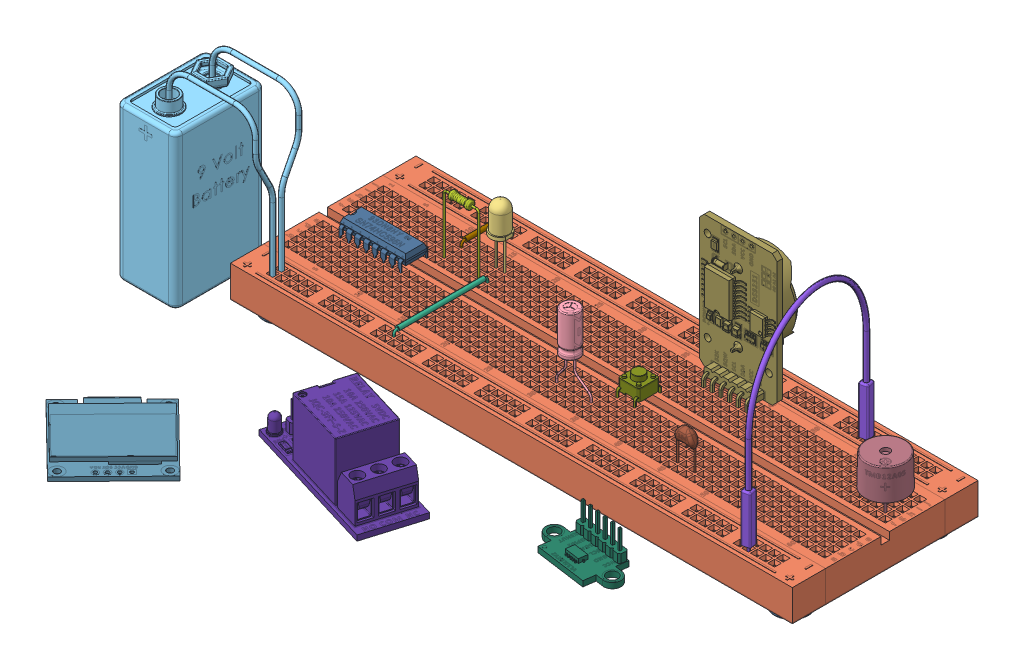
SolidWorks assembly BREADBOARD Test Unit, configuration Default. Lengths in mm.
Overall size (190.32 64.05 125.75).
17 component instances, 17 part files, 38 mates.
Components (placement in the parent):
- Breadboard Footpads-1: Breadboard Footpads [Default] at origin size (161.04 2.95 51.04)
- Breadboard-1: Breadboard [Default] at (0 3.15 0) x (0 0 -1) z (1 0 0) size (54.5 9.3 165)
- LED-Red-1: LED-Red [Default] at (-41.91 20.65 -11.43) x (0 0 -1) z (1 0 0) size (5.7 26.25 5.45)
- Bent Cap-1: Bent Cap [Default] at (-1.08 20.6268 8.89) x (0 0 1) z (-1 0 0) size (5.3 27.48 10.66)
- 9-Volt Battery-1: 9-Volt Battery [Default] at (-99.0282 0 22.375) x (0 0 1) z (-1 0 0) size (26.47 55.61 34.84)
- Jumper Wire BLACK GND-1: Jumper Wire BLACK GND [Default] at (-40.64 12.9 7.3775) x (0 0 -1) z (1 0 0) size (28.05 6.65 1.3)
- Resistor 470 Ohm-1: Resistor 470 Ohm [Default] at (-48.26 28.55 -6.35) size (10.69 26.62 2.44)
- Duport M-M Wire RED-01-1: Duport M-M Wire RED-01 [Default] at (60.96 13.25 1.2699) x (-0.221404 0 -0.975182) z (0.975182 0 -0.221404) size (48.43 57.2 2.54)
- Jumper Wire RED-1: Jumper Wire RED [Default] at (-53.34 12.9 -16.2675) x (0 0 -1) z (1 0 0) size (10.27 6.65 1.3)
- SN74HC595N Shift Register-1: SN74HC595N Shift Register [Default] at (-64.77 14.2 0) x (0 0 -1) z (1 0 0) size (7.9 7.3 19.3)
- Capacitor Ceramic 104 100nf-2: Capacitor Ceramic 104 100nf [Default] at (35.56 17.6608 11.43) size (5.72 13.92 2.54)
- DS3231 RTC-1: DS3231 RTC [Default] at (24.13 32.3828 -15.23) x (0 1 0) z (0 0 1) size (44.75 22.8 13.53)
- Buzzer Active 5V-1: Buzzer Active 5V [Default] at (73.5456 15.2644 -9.0832) x (0.717364 0 -0.696699) z (0.696699 0 0.717364) size (12 15 12)
- 0.96 Inch OLED Display Module I2C-1: 0.96 Inch OLED Display Module I2C [Default] at (-65.2768 2.2 78.9509) x (-0.714956 0 -0.69917) z (0.69917 0 -0.714956) size (27.8 4.2 27.5)
- Laser Ranging Sensor VL53L0XV2-1: Laser Ranging Sensor VL53L0XV2 [Default] at (33.9624 3 40.0946) x (-0.99046 0 -0.137803) z (0.137803 0 -0.99046) size (25 11.2 12)
- Push-Button Switch-1: Push-Button Switch [Default] at (10.16 15.8653 0) x (0 0 1) z (-1 0 0) size (7.62 8 6.06)
- Relay Module 5V-1: Relay Module 5V [Default] at (-21.6624 3.4 54.6215) x (0.289864 0 -0.957068) z (0.957068 0 0.289864) size (17.1 20.7 43)
Mates (geometry in assembly coordinates):
- Coincident1: coincident anti-aligned: plane of Breadboard Footpads-1 through (0 2.95 0) normal (0 1 0); plane of Breadboard-1 through (0 2.95 0) normal (0 -1 0)
- Width1: width anti-aligned: plane of Breadboard-1 through (-82.5 177.4378 27.25) normal (0 0 1); plane of Breadboard Footpads-1 through (-82.5 177.4378 -27.25) normal (0 0 -1); plane of Breadboard-1 through (-10 0.95 -7.5) normal (0 0 -1); plane of Breadboard Footpads-1 through (-10 0.95 7.5) normal (0 0 1)
- Width2: width aligned: plane of Breadboard Footpads-1 through (10 0.95 -7.5) normal (1 0 0); plane of Breadboard-1 through (-10 0.95 -7.5) normal (-1 0 0); plane of Breadboard Footpads-1 through (82.5 12.15 17.5) normal (1 0 0); plane of Breadboard-1 through (-82.5 12.15 17.5) normal (-1 0 0)
- Concentric1: concentric aligned: cylinder of Breadboard-1 through (-43.18 1.7358 -11.43) axis (0 1 0) radius 0.5; cylinder of LED-Red-1 through (-43.18 4.65 -11.43) axis (0 1 0) radius 0.25
- Parallel1: parallel aligned: cylinder of Breadboard-1 through (-40.64 1.7358 -11.43) axis (0 1 0) radius 0.5; cylinder of LED-Red-1 through (-40.64 4.65 -11.43) axis (0 1 0) radius 0.25
- Coincident2: coincident anti-aligned: plane of Breadboard-1 through (0 3.15 0) normal (0 1 0); plane of LED-Red-1 through (-43.18 3.15 -11.43) normal (0 -1 0)
- Concentric4: concentric aligned: cylinder of Breadboard-1 through (-40.64 1.7358 -11.43) axis (0 1 0) radius 0.5; cylinder of LED-Red-1 through (-40.64 4.65 -11.43) axis (0 1 0) radius 0.25
- Concentric5: concentric anti-aligned: cylinder of Breadboard-1 through (-5.08 1.7358 8.89) axis (0 1 0) radius 0.5; cylinder of Bent Cap-1 through (-5.08 12.4586 8.89) axis (0 -1 0) radius 0.25
- Concentric6: concentric anti-aligned: cylinder of Breadboard-1 through (5.08 1.7358 8.89) axis (0 1 0) radius 0.5; cylinder of Bent Cap-1 through (5.08 12.118 8.89) axis (0 -1 0) radius 0.25
- Distance1: distance = 2 mm anti-aligned: plane of Breadboard-1 through (0 3.15 0) normal (0 1 0); plane of Bent Cap-1 through (-5.08 5.15 8.89) normal (0 -1 0)
- Concentric7: concentric aligned: cylinder of Breadboard-1 through (-73.66 1.7358 23.645) axis (0 1 0) radius 0.5; cylinder of 9-Volt Battery-1 through (-73.66 0.958 23.645) axis (0 1 0) radius 0.25
- Concentric8: concentric aligned: cylinder of Breadboard-1 through (-73.66 1.7358 21.105) axis (0 1 0) radius 0.5; cylinder of 9-Volt Battery-1 through (-73.66 0.958 21.105) axis (0 1 0) radius 0.25
- Coincident4: coincident aligned: plane of Breadboard Footpads-1 through (-75 0 20) normal (0 -1 0); plane of 9-Volt Battery-1 through (-92.2972 0 11.199) normal (0 -1 0)
- Tangent1: tangent anti-aligned: plane of Breadboard-1 through (0 12.25 0) normal (0 1 0); cylinder of Jumper Wire BLACK GND-1 through (-40.64 12.9 -5.35) axis (0 0 1) radius 0.65
- Concentric13: concentric anti-aligned: cylinder of Breadboard-1 through (-40.64 1.7358 21.105) axis (0 1 0) radius 0.5; cylinder of Jumper Wire BLACK GND-1 through (-40.64 11.9 21.105) axis (0 -1 0) radius 0.3
- Concentric14: concentric aligned: cylinder of Breadboard-1 through (-40.64 1.7358 -6.35) axis (0 1 0) radius 0.5; cylinder of Jumper Wire BLACK GND-1 through (-40.64 6.9 -6.35) axis (0 1 0) radius 0.3
- Coincident5: coincident: plane of Breadboard-1 through (0 3.15 0) normal (0 1 0); plane of Resistor 470 Ohm-1 through (-52.9725 3.15 -3.6423) normal (0 -1 0)
- Concentric18: concentric aligned: cylinder of Breadboard-1 through (66.04 1.7358 23.645) axis (0 1 0) radius 0.5; cylinder of Duport M-M Wire RED-01-1 through (66.04 6.75 23.645) axis (0 1 0) radius 0.35
- Concentric19: concentric aligned: cylinder of Breadboard-1 through (55.88 1.7358 -21.105) axis (0 1 0) radius 0.5; cylinder of Duport M-M Wire RED-01-1 through (55.88 6.75 -21.1051) axis (0 1 0) radius 0.35
- Distance2: distance = 1 mm anti-aligned: plane of Breadboard-1 through (0 12.25 0) normal (0 1 0); plane of Duport M-M Wire RED-01-1 through (60.96 13.25 1.2699) normal (0 -1 0)
- Concentric20: concentric anti-aligned: cylinder of Breadboard-1 through (-53.34 1.7358 -11.43) axis (0 1 0) radius 0.5; cylinder of Jumper Wire RED-1 through (-53.34 11.9 -11.43) axis (0 -1 0) radius 0.3
- Concentric21: concentric aligned: cylinder of Breadboard-1 through (-53.34 1.7358 -21.105) axis (0 1 0) radius 0.5; cylinder of Jumper Wire RED-1 through (-53.34 6.9 -21.105) axis (0 1 0) radius 0.3
- Tangent2: tangent anti-aligned: plane of Breadboard-1 through (0 12.25 -44.75) normal (0 1 0); cylinder of Jumper Wire RED-1 through (-53.34 12.9 -20.105) axis (0 0 1) radius 0.65
- Concentric22: concentric anti-aligned: cylinder of SN74HC595N Shift Register-1 through (-55.88 8.5 3.81) axis (0 -1 0) radius 0.05; cylinder of Breadboard-1 through (-55.88 1.7358 3.81) axis (0 1 0) radius 0.5
- Perpendicular1: perpendicular: plane of Breadboard-1 through (-85.8302 12.15 -1.25) normal (0 0 1); plane of SN74HC595N Shift Register-1 through (-55.12 12.65 3.15) normal (1 0 0)
- Distance3: distance = 0.5 mm anti-aligned: plane of SN74HC595N Shift Register-1 through (-64.77 12.65 0) normal (0 -1 0); plane of Breadboard-1 through (0 12.15 0) normal (0 1 0)
- Concentric23: concentric aligned: cylinder of Breadboard-1 through (38.1 1.7358 11.43) axis (0 1 0) radius 0.5; cylinder of Capacitor Ceramic 104 100nf-2 through (38.1 7.6608 11.43) axis (0 1 0) radius 0.25
- Concentric24: concentric anti-aligned: cylinder of Breadboard-1 through (33.02 1.7358 11.43) axis (0 1 0) radius 0.5; cylinder of Capacitor Ceramic 104 100nf-2 through (33.02 17.1983 11.43) axis (0 -1 0) radius 0.25
- Concentric25: concentric anti-aligned: cylinder of Breadboard-1 through (17.78 1.7358 -11.43) axis (0 1 0) radius 0.5; cylinder of DS3231 RTC-1 through (17.78 6.9828 -11.43) axis (0 -1 0) radius 0.05
- Parallel3: parallel aligned: plane of Breadboard-1 through (-85.8302 12.15 -1.25) normal (0 0 1); plane of DS3231 RTC-1 through (24.13 32.3828 -15.23) normal (0 0 1)
- Concentric26: concentric aligned: cylinder of Breadboard-1 through (76.2 1.7358 -6.35) axis (0 1 0) radius 0.5; cylinder of Buzzer Active 5V-1 through (76.2 10.7644 -6.35) axis (0 1 0) radius 0.3
- Coincident11: coincident aligned: plane of Breadboard Footpads-1 through (-75 0 20) normal (0 -1 0); plane of 0.96 Inch OLED Display Module I2C-1 through (-65.2768 0 78.9509) normal (0 -1 0)
- Coincident12: coincident aligned: plane of Breadboard Footpads-1 through (75 0 20) normal (0 -1 0); plane of Laser Ranging Sensor VL53L0XV2-1 through (33.9624 0 40.0946) normal (0 -1 0)
- Concentric27: concentric anti-aligned: cylinder of Breadboard-1 through (12.7 1.7358 3.81) axis (0 1 0) radius 0.5; cylinder of Push-Button Switch-1 through (12.7 12.4653 3.81) axis (0 -1 0) radius 1.5
- Perpendicular2: perpendicular: plane of Breadboard-1 through (-85.8302 12.15 -1.25) normal (0 0 1); plane of Push-Button Switch-1 through (13.19 12.3653 -3.03) normal (1 0 0)
- Coincident13: coincident aligned: plane of Breadboard Footpads-1 through (-75 0 20) normal (0 -1 0); plane of Relay Module 5V-1 through (-13.3194 0 50.8791) normal (0 -1 0)
- Concentric28: concentric: cylinder of Breadboard-1 through (-43.18 1.7358 -6.35) axis (0 1 0) radius 0.5; cylinder of Resistor 470 Ohm-1 through (-43.18 3.15 -6.35) axis (0 1 0) radius 0.265
- Concentric29: concentric anti-aligned: cylinder of Breadboard-1 through (-53.34 1.7358 -6.35) axis (0 1 0) radius 0.5; cylinder of Resistor 470 Ohm-1 through (-53.34 27.8 -6.35) axis (0 -1 0) radius 0.265
